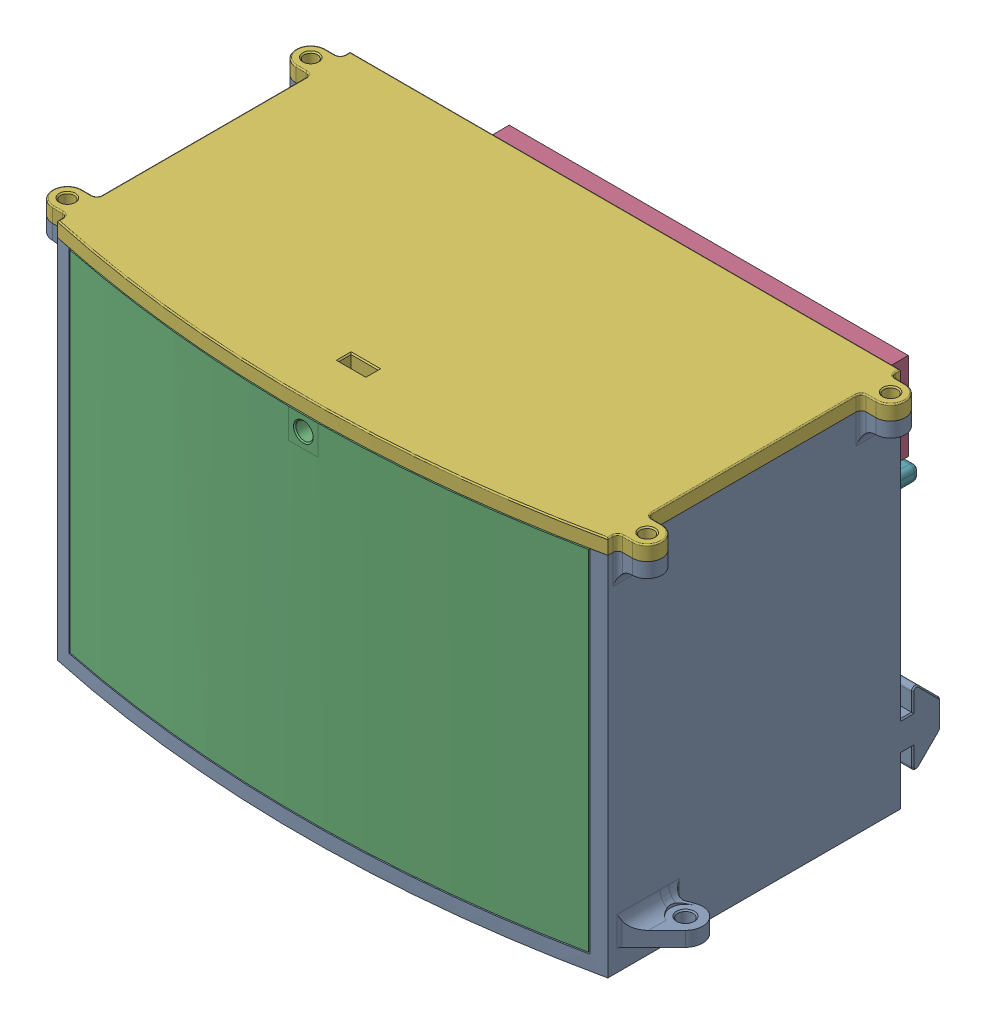
SolidWorks assembly Charger Box Assembly, configuration Default. Lengths in mm.
Overall size (127.54 77.5 82.51).
8 component instances, 8 part files, 23 mates.
Components (placement in the parent):
- Charger Box - Base-1: Charger Box - Base [Default] at (37.798 34.5608 48.4871) size (127.54 74.5 73.71)
- XLR Female-1: XLR Female [Default] at (37.798 52.7858 48.4871) x (-1 0 0) z (0 0 -1) size (18 18 58.51)
- Charger Box - Latch-1: Charger Box - Latch [Default] at (37.793 37.8108 104.7065) x (1 0 0.000019) z (-0.000019 0 1) size (105.54 72.75 7.55)
- Circuit Breaker-1: Circuit Breaker [Default] at (37.798 80.5108 53.4871) size (81.2 17.8 66)
- SPDT Switch-1: SPDT Switch [Default] at (7.298 60.4108 61.5871) size (16 28.7 54.25)
- Charger Box - Lid-1: Charger Box - Lid [Default] at (37.798 109.0608 48.4871) x (1 0 0) z (0 1 0) size (124 65.51 11)
- Charger Box - IO Slide-1: Charger Box - IO Slide [Default] at (37.798 34.5608 78.4871) size (108.5 74 52.75)
- SPDT Switch Ring-1: SPDT Switch Ring [Default] at (7.298 60.4108 81.2371) size (15 15 2.55)
Mates (geometry in assembly coordinates):
- Coincident2: coincident anti-aligned: plane of Bottom - Wifi + PowerSocket Mount-1 through (-15.202 37.5608 48.4871) normal (0 0 1); plane of XLR Female-1 through (37.798 52.7858 48.4871) normal (0 0 -1)
- Parallel1: parallel aligned: plane of Bottom - Wifi + PowerSocket Mount-1 through (37.798 37.5608 -154.7593) normal (0 1 0); plane of XLR Female-1 through (33.9619 57.5608 98.4572) normal (0 1 0)
- Distance1: distance = 0.25 mm anti-aligned: plane of PowerSocket Latch-1 through (37.798 37.8108 -156.7593) normal (0 -1 0); plane of Bottom - Wifi + PowerSocket Mount-1 through (37.798 37.5608 -154.7593) normal (0 1 0)
- Concentric3: concentric aligned: cylinder of Bottom - Wifi + PowerSocket Mount-1 through (37.798 37.5608 -154.7593) axis (0 -1 0) radius 265.7536; cylinder of PowerSocket Latch-1 through (37.798 108.8108 -154.7593) axis (0 -1 0) radius 265.7536
- Distance3: distance = 0.25 mm: line of PowerSocket Latch-1 through (-14.957 108.8108 105.7055) axis (0 -1 0); line of Bottom - Wifi + PowerSocket Mount-1 through (-15.202 109.0608 105.6557) axis (0 -1 0)
- Coincident4: coincident aligned: plane of Bottom - Wifi + PowerSocket Mount-1 through (-16.702 -74.4804 78.4871) normal (0 0 1); plane of SPDT Switch-1 through (7.298 60.4108 78.4871) normal (0 0 1)
- Coincident5: coincident aligned: plane of Bottom - Wifi + PowerSocket Mount-1 through (-16.702 -74.4804 78.4871) normal (0 0 1); plane of Circuit Breaker-1 through (-2.802 98.3108 78.4871) normal (0 0 1)
- Distance4: distance = 14.5 mm anti-aligned: plane of SPDT Switch-1 through (-0.702 46.0608 76.0871) normal (-1 0 0); plane of Bottom - Wifi + PowerSocket Mount-1 through (-15.202 37.5608 105.6557) normal (1 0 0)
- Distance5: distance = 12.4 mm anti-aligned: plane of Circuit Breaker-1 through (-2.802 98.3108 78.4871) normal (-1 0 0); plane of Bottom - Wifi + PowerSocket Mount-1 through (-15.202 37.5608 105.6557) normal (1 0 0)
- Distance6: distance = 8.5 mm anti-aligned: plane of Bottom - Wifi + PowerSocket Mount-1 through (37.798 37.5608 -154.7593) normal (0 1 0); plane of SPDT Switch-1 through (-0.702 46.0608 76.0871) normal (0 -1 0)
- Distance7: distance = 20 mm aligned: plane of XLR Female-1 through (33.9619 57.5608 98.4572) normal (0 1 0); plane of Bottom - Wifi + PowerSocket Mount-1 through (37.798 37.5608 -154.7593) normal (0 1 0)
- InPlace1: in place: plane of Charger Box - Base-1 through (37.798 109.0608 -154.7593) normal (0 1 0); plane of ? through (0 109.0608 0) normal (0 1 0); moOrthogonalPlaneRef_w of Charger Box - Base-1 through (37.798 109.0608 -154.7593) normal (0 1 0); plane of ? through (0 109.0608 0) normal (0 0 -1); plane of Charger Box - Base-1 through (37.798 109.0608 -154.7593) normal (0 1 0); plane of ? through (0 109.0608 0) normal (1 0 0); plane of Charger Box - Base-1 through (37.798 109.0608 -154.7593) normal (0 1 0); unknown of Charger Box - Lid-1
- Coincident6: coincident aligned: plane of ?; plane of ?
- Coincident7: coincident aligned: moOrthogonalPlaneRef_w of Bottom - Wifi + PowerSocket Mount-1 through (37.798 109.0608 48.4871) normal (0 0 -1); plane of Bottom - Wifi Lid-1 through (37.798 109.0608 48.4871) normal (0 0 -1)
- Coincident8: coincident anti-aligned: moOrthogonalPlaneRef_w of Bottom - Wifi + PowerSocket Mount-1 through (37.798 109.0608 48.4871) normal (-1 0 0); plane of Bottom - Wifi Lid-1 through (37.798 109.0608 48.4871) normal (1 0 0)
- InPlace2: in place: plane of Charger Box - Base-1 through (-16.702 -74.4804 78.4871) normal (0 0 1); plane of ? through (0 0 78.4871) normal (0 0 1); plane of Charger Box - Base-1 through (-16.702 -74.4804 78.4871) normal (0 0 1); plane of ? through (0 0 78.4871) normal (0 1 0); plane of Charger Box - Base-1 through (-16.702 -74.4804 78.4871) normal (0 0 1); plane of ? through (0 0 78.4871) normal (1 0 0); plane of Charger Box - Base-1 through (-16.702 -74.4804 78.4871) normal (0 0 1); unknown of Charger Box - IO Slide-1
- Coincident9: coincident aligned: plane of ?; plane of ?
- Coincident10: coincident aligned: moOrthogonalPlaneRef_w of Bottom - Wifi + PowerSocket Mount-1 through (37.798 34.5608 78.4871) normal (0 1 0); plane of Bottom - PowerSocket Component Mount-1 through (37.798 34.5608 78.4871) normal (0 1 0)
- Coincident11: coincident anti-aligned: moOrthogonalPlaneRef_w of Bottom - Wifi + PowerSocket Mount-1 through (37.798 34.5608 78.4871) normal (-1 0 0); plane of Bottom - PowerSocket Component Mount-1 through (37.798 34.5608 78.4871) normal (1 0 0)
- Distance9: distance = 2.75 mm anti-aligned: plane of Circuit Breaker-1 through (37.798 98.3108 53.4871) normal (0 1 0); plane of Bottom - Wifi Lid-1 through (37.798 101.0608 48.4871) normal (0 -1 0)
- Distance10: distance = 49.164 mm: point of XLR Female-1; plane of Bottom - Wifi + PowerSocket Mount-1 through (-15.202 37.5608 105.6557) normal (1 0 0)
- Coincident14: coincident anti-aligned: plane of Bottom - PowerSocket Component Mount-1 through (-16.702 -74.4804 81.2371) normal (0 0 1); plane of SPDT Switch Ring-1 through (7.298 60.4108 81.2371) normal (0 0 -1)
- Concentric8: concentric aligned: cylinder of SPDT Switch-1 through (7.298 60.4108 88.9871) axis (0 0 -1) radius 5.85; cylinder of SPDT Switch Ring-1 through (7.298 60.4108 83.7871) axis (0 0 -1) radius 5.55
